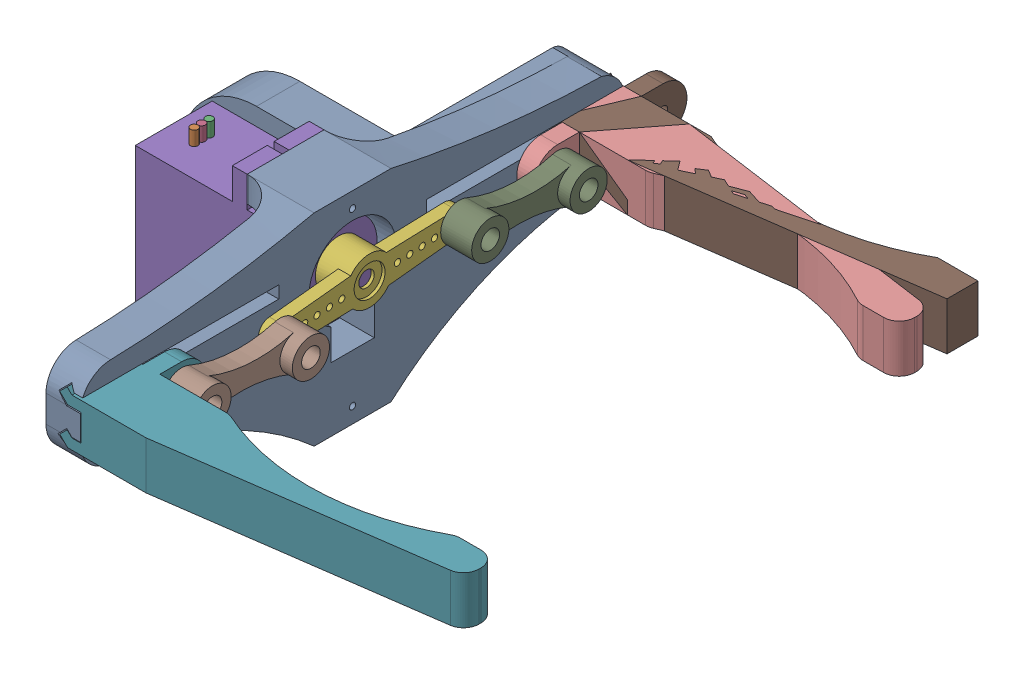
SolidWorks assembly Linear Gripper, configuration Default. Lengths in mm.
Overall size (91.53 33.39 95.08).
7 component instances, 6 part files, 16 mates.
Components (placement in the parent):
- Linear Base-1: Linear Base [Default] at origin size (35.83 33.39 87.8)
- Servo Micro-2: Servo Micro [Default] at (-5.15 0.0047 15.2) x (0 -1 0) z (0 0 1) size (32.6 29.9 12.4)
- Horn-1: Horn [По умолчанию] at (26.45 5.1047 15.2) x (0 0.069042 -0.997614) z (-1 0 0) size (32 7.5 5)
- LGrip-1: LGrip [Default] at (23.7 3.1845 54.0339) x (0 0 -1) z (1 0 0) size (17.35 8.47 59.1)
- Linear Link-1: Linear Link [Default] at (29.45 4.6042 37.5996) x (0 -0.062963 -0.998016) z (0 0.998016 -0.062963) size (21.9 5 6)
- Linear Link-2: Linear Link [Default] at (29.45 5.6053 -7.1996) x (0 -0.062963 -0.998016) z (0 0.998016 -0.062963) size (21.9 5 6)
- LGrip Mirror-1: LGrip Mirror [Default] at (23.7 3.1845 -23.6339) x (0 0 -1) z (1 0 0) size (24.7 8.47 59.1)
Mates (geometry in assembly coordinates):
- Parallel1: parallel aligned: plane of Linear Base-1 through (4.3155 0 7) normal (0 0 1); plane of Servo Micro-2 through (17.15 11.3047 21.4) normal (0 0 1)
- Coincident8: coincident anti-aligned: plane of Linear Base-1 through (12.9 16.3047 21.4) normal (-1 0 0); plane of Servo Micro-2 through (12.9 16.3047 21.4) normal (1 0 0)
- Concentric2: concentric anti-aligned: circle of Servo Micro-2; circle of Horn-1
- Coincident11: coincident anti-aligned: plane of Servo Micro-2 through (21.45 0.0047 15.2) normal (1 0 0); plane of Horn-1 through (21.45 5.1047 15.2) normal (-1 0 0)
- Concentric3: concentric aligned: circle of Linear Base-1; circle of Servo Micro-2
- Coincident12: coincident anti-aligned: plane of Linear Base-1 through (23.7 0 -23) normal (1 0 0); plane of LGrip-1 through (23.7 3.1845 54.0339) normal (-1 0 0)
- Distance3: distance = 0.15 mm anti-aligned: plane of Linear Base-1 through (0 9.1047 27.1) normal (0 -1 0); plane of LGrip-1 through (23.55 8.9547 44.8319) normal (0 1 0)
- Concentric4: concentric anti-aligned: circle of LGrap-1; circle of Linear Link-1
- Concentric5: concentric aligned: circle of Horn-1; circle of Linear Link-1
- Coincident17: coincident anti-aligned: plane of Horn-1 through (26.45 5.1047 15.2) normal (1 0 0); plane of Linear Link-1 through (26.45 5.1047 45.5339) normal (-1 0 0)
- LimitDistance1: limit distance = 21.9339 mm anti-aligned: plane of LGrip-1 through (28.7 -2.6337 49.0339) normal (0 0 -1); plane of Linear Base-1 through (0 0 27.1) normal (0 0 1)
- Concentric6: concentric anti-aligned: circle of Horn-1; circle of Linear Link-2
- Coincident20: coincident anti-aligned: plane of Horn-1 through (26.45 5.1047 15.2) normal (1 0 0); plane of Linear Link-2 through (26.45 6.1058 0.7346) normal (-1 0 0)
- Coincident21: coincident anti-aligned: plane of Linear Base-1 through (23.7 0 -23) normal (1 0 0); plane of LGrip Mirror-1 through (23.7 3.1845 -23.6339) normal (-1 0 0)
- Distance4: distance = 0.15 mm anti-aligned: plane of LGrip Mirror-1 through (23.55 8.9547 -14.4319) normal (0 1 0); plane of Linear Base-1 through (0 9.1047 3.3) normal (0 -1 0)
- Concentric7: concentric aligned: circle of Linear Link-2; circle of LGrip Mirror-1
